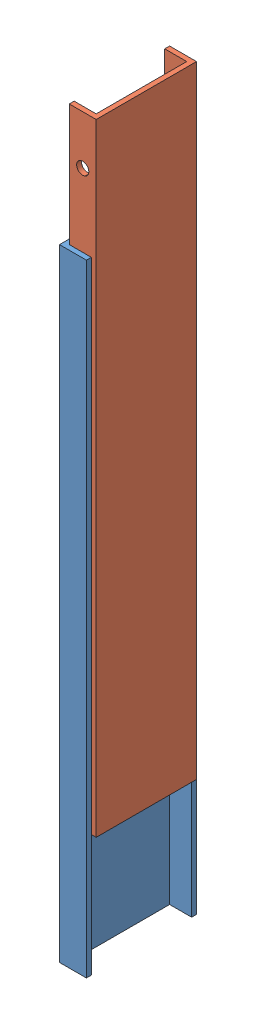
SolidWorks assembly Amazon_B01MS9NW0R, configuration Default. Lengths in mm.
Overall size (13 303.77 45).
2 component instances, 2 part files, 3 mates.
Components (placement in the parent):
- DrawerGlide-Outer-1: DrawerGlide-Outer [Default] at (68.9465 5.8419 178.7008) size (11 254 45)
- DrawerGlide-Inner-1: DrawerGlide-Inner [Default] at (81.9465 55.6082 135.7008) x (-1 0 0) z (0 0 -1) size (11 254 41)
Mates (geometry in assembly coordinates):
- Coincident1: coincident anti-aligned: plane of DrawerGlide-Outer-1 through (70.9465 259.8419 135.7008) normal (1 0 0); plane of DrawerGlide-Inner-1 through (70.9465 309.6082 137.7008) normal (-1 0 0)
- Coincident2: coincident anti-aligned: plane of DrawerGlide-Outer-1 through (79.9465 259.8419 135.7008) normal (0 0 1); plane of DrawerGlide-Inner-1 through (70.9465 309.6082 135.7008) normal (0 0 -1)
- LimitDistance1: limit distance = 49.7663 mm aligned: plane of DrawerGlide-Outer-1 through (68.9465 259.8419 178.7008) normal (0 1 0); plane of DrawerGlide-Inner-1 through (81.9465 309.6082 135.7008) normal (0 1 0)
